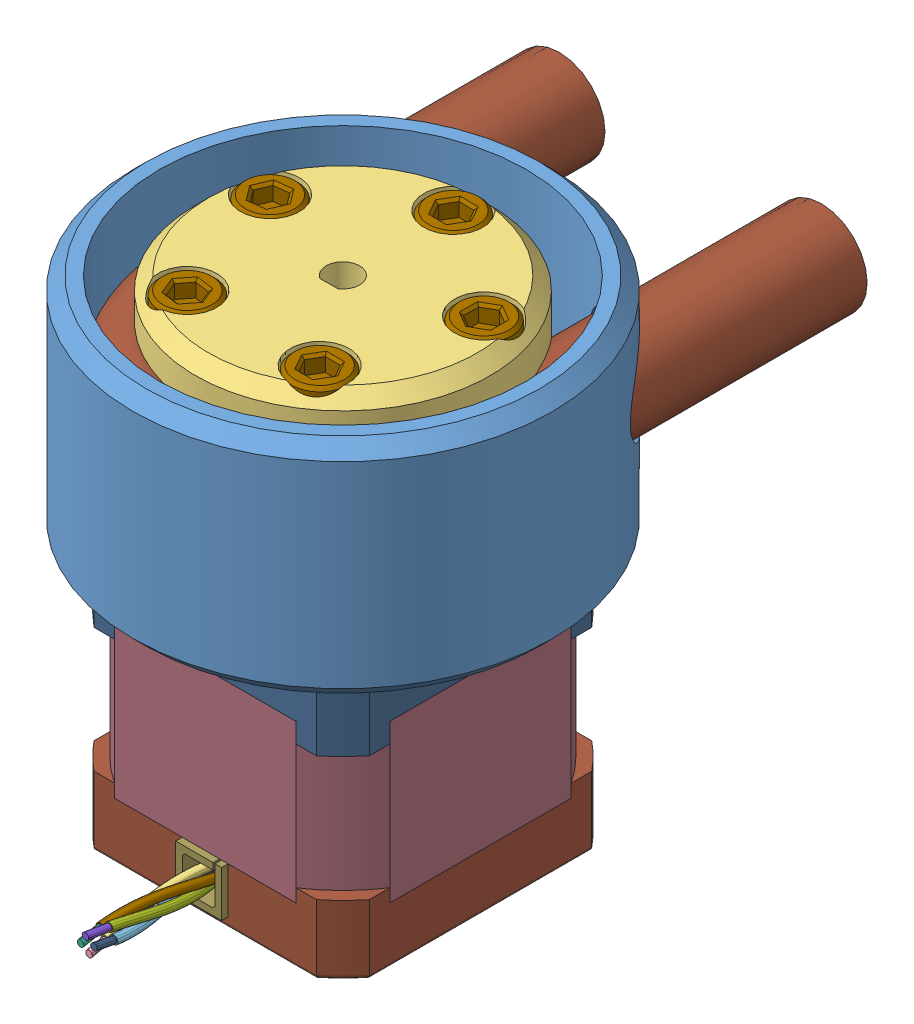
SolidWorks assembly pump, configuration Default. Lengths in mm.
Overall size (64 74.29 92).
174 component instances, 31 part files, 74 mates.
Components (placement in the parent):
- pump-shell-1: pump-shell [Default] at (23.8184 9.0777 41.5855) size (64 34 64)
- bottom-plate-1: bottom-plate [Default] at (23.8184 23.0777 41.5855) x (-0.999957 0 0.009262) z (0.009262 0 0.999957) size (52 18 52)
- top-plate-1: top-plate [Default] at (23.8184 35.0777 41.5855) x (-0.814427 0 -0.580267) z (0.580267 0 -0.814427) size (45 8.29 45)
- 625zz.STEP-1: 625zz.STEP [Default] at (23.8184 16.0777 41.5855) x (0 -1 0) z (-0.839089 0 -0.543994) size (5 16 16)
  - SKF 625 Inner Race^SKF 625.STEP-1: SKF 625 Inner Race^SKF 625.STEP [Default] at origin size (5 8.4 8.4)
  - SKF 625 Outer Race^SKF 625.STEP-1: SKF 625 Outer Race^SKF 625.STEP [Default] at origin size (5 16 16)
  - SKF 625 Ball^SKF 625.STEP-1: SKF 625 Ball^SKF 625.STEP [Default] at origin size (2.38 2.38 2.38)
  - SKF 625 Ball^SKF 625.STEP-2: SKF 625 Ball^SKF 625.STEP [Default] x (1 0 0) z (0 0.707107 0.707107) size (2.38 2.38 2.38)
  - SKF 625 Ball^SKF 625.STEP-3: SKF 625 Ball^SKF 625.STEP [Default] x (1 0 0) z (0 1 0) size (2.38 2.38 2.38)
  - SKF 625 Ball^SKF 625.STEP-4: SKF 625 Ball^SKF 625.STEP [Default] x (1 0 0) z (0 0.707107 -0.707107) size (2.38 2.38 2.38)
  - SKF 625 Ball^SKF 625.STEP-5: SKF 625 Ball^SKF 625.STEP [Default] x (1 0 0) z (0 0 -1) size (2.38 2.38 2.38)
  - SKF 625 Ball^SKF 625.STEP-6: SKF 625 Ball^SKF 625.STEP [Default] x (1 0 0) z (0 -0.707107 -0.707107) size (2.38 2.38 2.38)
  - SKF 625 Ball^SKF 625.STEP-7: SKF 625 Ball^SKF 625.STEP [Default] x (1 0 0) z (0 -1 0) size (2.38 2.38 2.38)
  - SKF 625 Ball^SKF 625.STEP-8: SKF 625 Ball^SKF 625.STEP [Default] x (1 0 0) z (0 -0.707107 0.707107) size (2.38 2.38 2.38)
  - SKF 625 Cage^SKF 625.STEP-1: SKF 625 Cage^SKF 625.STEP [Default] at (2.5 0 0) x (0 0 -1) z (1 0 0) size (12.17 12.17 2.88)
- m5-spacer-1: m5-spacer [Default] at (23.8184 16.0777 41.5855) x (-0.754389 0 0.656427) z (-0.656427 0 -0.754389) size (10 1 10)
- 625zz.STEP-2: 625zz.STEP [Default] at (7.5901 29.0777 36.4783) x (0 -1 0) z (0 0 1) size (5 16 16)
  - SKF 625 Inner Race^SKF 625.STEP-1: SKF 625 Inner Race^SKF 625.STEP [Default] at origin size (5 8.4 8.4)
  - SKF 625 Outer Race^SKF 625.STEP-1: SKF 625 Outer Race^SKF 625.STEP [Default] at origin size (5 16 16)
  - SKF 625 Ball^SKF 625.STEP-1: SKF 625 Ball^SKF 625.STEP [Default] at origin size (2.38 2.38 2.38)
  - SKF 625 Ball^SKF 625.STEP-2: SKF 625 Ball^SKF 625.STEP [Default] x (1 0 0) z (0 0.707107 0.707107) size (2.38 2.38 2.38)
  - SKF 625 Ball^SKF 625.STEP-3: SKF 625 Ball^SKF 625.STEP [Default] x (1 0 0) z (0 1 0) size (2.38 2.38 2.38)
  - SKF 625 Ball^SKF 625.STEP-4: SKF 625 Ball^SKF 625.STEP [Default] x (1 0 0) z (0 0.707107 -0.707107) size (2.38 2.38 2.38)
  - SKF 625 Ball^SKF 625.STEP-5: SKF 625 Ball^SKF 625.STEP [Default] x (1 0 0) z (0 0 -1) size (2.38 2.38 2.38)
  - SKF 625 Ball^SKF 625.STEP-6: SKF 625 Ball^SKF 625.STEP [Default] x (1 0 0) z (0 -0.707107 -0.707107) size (2.38 2.38 2.38)
  - SKF 625 Ball^SKF 625.STEP-7: SKF 625 Ball^SKF 625.STEP [Default] x (1 0 0) z (0 -1 0) size (2.38 2.38 2.38)
  - SKF 625 Ball^SKF 625.STEP-8: SKF 625 Ball^SKF 625.STEP [Default] x (1 0 0) z (0 -0.707107 0.707107) size (2.38 2.38 2.38)
  - SKF 625 Cage^SKF 625.STEP-1: SKF 625 Cage^SKF 625.STEP [Default] at (2.5 0 0) x (0 0 -1) z (1 0 0) size (12.17 12.17 2.88)
- 625zz.STEP-3: 625zz.STEP [Default] at (7.5901 34.0777 36.4783) x (0 -1 0) z (0.968021 0 0.25087) size (5 16 16)
  - SKF 625 Inner Race^SKF 625.STEP-1: SKF 625 Inner Race^SKF 625.STEP [Default] at origin size (5 8.4 8.4)
  - SKF 625 Outer Race^SKF 625.STEP-1: SKF 625 Outer Race^SKF 625.STEP [Default] at origin size (5 16 16)
  - SKF 625 Ball^SKF 625.STEP-1: SKF 625 Ball^SKF 625.STEP [Default] at origin size (2.38 2.38 2.38)
  - SKF 625 Ball^SKF 625.STEP-2: SKF 625 Ball^SKF 625.STEP [Default] x (1 0 0) z (0 0.707107 0.707107) size (2.38 2.38 2.38)
  - SKF 625 Ball^SKF 625.STEP-3: SKF 625 Ball^SKF 625.STEP [Default] x (1 0 0) z (0 1 0) size (2.38 2.38 2.38)
  - SKF 625 Ball^SKF 625.STEP-4: SKF 625 Ball^SKF 625.STEP [Default] x (1 0 0) z (0 0.707107 -0.707107) size (2.38 2.38 2.38)
  - SKF 625 Ball^SKF 625.STEP-5: SKF 625 Ball^SKF 625.STEP [Default] x (1 0 0) z (0 0 -1) size (2.38 2.38 2.38)
  - SKF 625 Ball^SKF 625.STEP-6: SKF 625 Ball^SKF 625.STEP [Default] x (1 0 0) z (0 -0.707107 -0.707107) size (2.38 2.38 2.38)
  - SKF 625 Ball^SKF 625.STEP-7: SKF 625 Ball^SKF 625.STEP [Default] x (1 0 0) z (0 -1 0) size (2.38 2.38 2.38)
  - SKF 625 Ball^SKF 625.STEP-8: SKF 625 Ball^SKF 625.STEP [Default] x (1 0 0) z (0 -0.707107 0.707107) size (2.38 2.38 2.38)
  - SKF 625 Cage^SKF 625.STEP-1: SKF 625 Cage^SKF 625.STEP [Default] at (2.5 0 0) x (0 0 -1) z (1 0 0) size (12.17 12.17 2.88)
- 625zz.STEP-4: 625zz.STEP [Default] at (33.9455 29.0777 55.2561) x (0 1 0) z (0 0 1) size (5 16 16)
  - SKF 625 Inner Race^SKF 625.STEP-1: SKF 625 Inner Race^SKF 625.STEP [Default] at origin size (5 8.4 8.4)
  - SKF 625 Outer Race^SKF 625.STEP-1: SKF 625 Outer Race^SKF 625.STEP [Default] at origin size (5 16 16)
  - SKF 625 Ball^SKF 625.STEP-1: SKF 625 Ball^SKF 625.STEP [Default] at origin size (2.38 2.38 2.38)
  - SKF 625 Ball^SKF 625.STEP-2: SKF 625 Ball^SKF 625.STEP [Default] x (1 0 0) z (0 0.707107 0.707107) size (2.38 2.38 2.38)
  - SKF 625 Ball^SKF 625.STEP-3: SKF 625 Ball^SKF 625.STEP [Default] x (1 0 0) z (0 1 0) size (2.38 2.38 2.38)
  - SKF 625 Ball^SKF 625.STEP-4: SKF 625 Ball^SKF 625.STEP [Default] x (1 0 0) z (0 0.707107 -0.707107) size (2.38 2.38 2.38)
  - SKF 625 Ball^SKF 625.STEP-5: SKF 625 Ball^SKF 625.STEP [Default] x (1 0 0) z (0 0 -1) size (2.38 2.38 2.38)
  - SKF 625 Ball^SKF 625.STEP-6: SKF 625 Ball^SKF 625.STEP [Default] x (1 0 0) z (0 -0.707107 -0.707107) size (2.38 2.38 2.38)
  - SKF 625 Ball^SKF 625.STEP-7: SKF 625 Ball^SKF 625.STEP [Default] x (1 0 0) z (0 -1 0) size (2.38 2.38 2.38)
  - SKF 625 Ball^SKF 625.STEP-8: SKF 625 Ball^SKF 625.STEP [Default] x (1 0 0) z (0 -0.707107 0.707107) size (2.38 2.38 2.38)
  - SKF 625 Cage^SKF 625.STEP-1: SKF 625 Cage^SKF 625.STEP [Default] at (2.5 0 0) x (0 0 -1) z (1 0 0) size (12.17 12.17 2.88)
- 625zz.STEP-5: 625zz.STEP [Default] at (33.9455 24.0777 55.2561) x (0 1 0) z (0.007155 0 0.999974) size (5 16 16)
  - SKF 625 Inner Race^SKF 625.STEP-1: SKF 625 Inner Race^SKF 625.STEP [Default] at origin size (5 8.4 8.4)
  - SKF 625 Outer Race^SKF 625.STEP-1: SKF 625 Outer Race^SKF 625.STEP [Default] at origin size (5 16 16)
  - SKF 625 Ball^SKF 625.STEP-1: SKF 625 Ball^SKF 625.STEP [Default] at origin size (2.38 2.38 2.38)
  - SKF 625 Ball^SKF 625.STEP-2: SKF 625 Ball^SKF 625.STEP [Default] x (1 0 0) z (0 0.707107 0.707107) size (2.38 2.38 2.38)
  - SKF 625 Ball^SKF 625.STEP-3: SKF 625 Ball^SKF 625.STEP [Default] x (1 0 0) z (0 1 0) size (2.38 2.38 2.38)
  - SKF 625 Ball^SKF 625.STEP-4: SKF 625 Ball^SKF 625.STEP [Default] x (1 0 0) z (0 0.707107 -0.707107) size (2.38 2.38 2.38)
  - SKF 625 Ball^SKF 625.STEP-5: SKF 625 Ball^SKF 625.STEP [Default] x (1 0 0) z (0 0 -1) size (2.38 2.38 2.38)
  - SKF 625 Ball^SKF 625.STEP-6: SKF 625 Ball^SKF 625.STEP [Default] x (1 0 0) z (0 -0.707107 -0.707107) size (2.38 2.38 2.38)
  - SKF 625 Ball^SKF 625.STEP-7: SKF 625 Ball^SKF 625.STEP [Default] x (1 0 0) z (0 -1 0) size (2.38 2.38 2.38)
  - SKF 625 Ball^SKF 625.STEP-8: SKF 625 Ball^SKF 625.STEP [Default] x (1 0 0) z (0 -0.707107 0.707107) size (2.38 2.38 2.38)
  - SKF 625 Cage^SKF 625.STEP-1: SKF 625 Cage^SKF 625.STEP [Default] at (2.5 0 0) x (0 0 -1) z (1 0 0) size (12.17 12.17 2.88)
- 625zz.STEP-6: 625zz.STEP [Default] at (13.9463 29.0777 55.4414) x (0 1 0) z (0.26967 0 0.962953) size (5 16 16)
  - SKF 625 Inner Race^SKF 625.STEP-1: SKF 625 Inner Race^SKF 625.STEP [Default] at origin size (5 8.4 8.4)
  - SKF 625 Outer Race^SKF 625.STEP-1: SKF 625 Outer Race^SKF 625.STEP [Default] at origin size (5 16 16)
  - SKF 625 Ball^SKF 625.STEP-1: SKF 625 Ball^SKF 625.STEP [Default] at origin size (2.38 2.38 2.38)
  - SKF 625 Ball^SKF 625.STEP-2: SKF 625 Ball^SKF 625.STEP [Default] x (1 0 0) z (0 0.707107 0.707107) size (2.38 2.38 2.38)
  - SKF 625 Ball^SKF 625.STEP-3: SKF 625 Ball^SKF 625.STEP [Default] x (1 0 0) z (0 1 0) size (2.38 2.38 2.38)
  - SKF 625 Ball^SKF 625.STEP-4: SKF 625 Ball^SKF 625.STEP [Default] x (1 0 0) z (0 0.707107 -0.707107) size (2.38 2.38 2.38)
  - SKF 625 Ball^SKF 625.STEP-5: SKF 625 Ball^SKF 625.STEP [Default] x (1 0 0) z (0 0 -1) size (2.38 2.38 2.38)
  - SKF 625 Ball^SKF 625.STEP-6: SKF 625 Ball^SKF 625.STEP [Default] x (1 0 0) z (0 -0.707107 -0.707107) size (2.38 2.38 2.38)
  - SKF 625 Ball^SKF 625.STEP-7: SKF 625 Ball^SKF 625.STEP [Default] x (1 0 0) z (0 -1 0) size (2.38 2.38 2.38)
  - SKF 625 Ball^SKF 625.STEP-8: SKF 625 Ball^SKF 625.STEP [Default] x (1 0 0) z (0 -0.707107 0.707107) size (2.38 2.38 2.38)
  - SKF 625 Cage^SKF 625.STEP-1: SKF 625 Cage^SKF 625.STEP [Default] at (2.5 0 0) x (0 0 -1) z (1 0 0) size (12.17 12.17 2.88)
- 625zz.STEP-7: 625zz.STEP [Default] at (13.9463 24.0777 55.4414) x (0 1 0) z (0.019727 0 0.999805) size (5 16 16)
  - SKF 625 Inner Race^SKF 625.STEP-1: SKF 625 Inner Race^SKF 625.STEP [Default] at origin size (5 8.4 8.4)
  - SKF 625 Outer Race^SKF 625.STEP-1: SKF 625 Outer Race^SKF 625.STEP [Default] at origin size (5 16 16)
  - SKF 625 Ball^SKF 625.STEP-1: SKF 625 Ball^SKF 625.STEP [Default] at origin size (2.38 2.38 2.38)
  - SKF 625 Ball^SKF 625.STEP-2: SKF 625 Ball^SKF 625.STEP [Default] x (1 0 0) z (0 0.707107 0.707107) size (2.38 2.38 2.38)
  - SKF 625 Ball^SKF 625.STEP-3: SKF 625 Ball^SKF 625.STEP [Default] x (1 0 0) z (0 1 0) size (2.38 2.38 2.38)
  - SKF 625 Ball^SKF 625.STEP-4: SKF 625 Ball^SKF 625.STEP [Default] x (1 0 0) z (0 0.707107 -0.707107) size (2.38 2.38 2.38)
  - SKF 625 Ball^SKF 625.STEP-5: SKF 625 Ball^SKF 625.STEP [Default] x (1 0 0) z (0 0 -1) size (2.38 2.38 2.38)
  - SKF 625 Ball^SKF 625.STEP-6: SKF 625 Ball^SKF 625.STEP [Default] x (1 0 0) z (0 -0.707107 -0.707107) size (2.38 2.38 2.38)
  - SKF 625 Ball^SKF 625.STEP-7: SKF 625 Ball^SKF 625.STEP [Default] x (1 0 0) z (0 -1 0) size (2.38 2.38 2.38)
  - SKF 625 Ball^SKF 625.STEP-8: SKF 625 Ball^SKF 625.STEP [Default] x (1 0 0) z (0 -0.707107 0.707107) size (2.38 2.38 2.38)
  - SKF 625 Cage^SKF 625.STEP-1: SKF 625 Cage^SKF 625.STEP [Default] at (2.5 0 0) x (0 0 -1) z (1 0 0) size (12.17 12.17 2.88)
- m5-spacer-2: m5-spacer [Default] at (13.9463 34.0777 55.4414) size (10 1 10)
- m5-spacer-3: m5-spacer [Default] at (13.9463 24.0777 55.4414) x (-0.837169 0 -0.546944) z (-0.546944 0 0.837169) size (10 1 10)
- m5-spacer-4: m5-spacer [Default] at (33.9455 24.0777 55.2561) x (-0.837169 0 -0.546944) z (-0.546944 0 0.837169) size (10 1 10)
- m5-spacer-5: m5-spacer [Default] at (39.9494 24.0777 36.1786) x (-0.837169 0 -0.546944) z (-0.546944 0 0.837169) size (10 1 10)
- m5-spacer-6: m5-spacer [Default] at (33.9455 34.0777 55.2561) size (10 1 10)
- m5-spacer-7: m5-spacer [Default] at (7.5901 34.0777 36.4783) x (-1 0 0) z (0 0 -1) size (10 1 10)
- m5-spacer-8: m5-spacer [Default] at (39.9494 34.0777 36.1786) x (-1 0 0) z (0 0 -1) size (10 1 10)
- m5-spacer-9: m5-spacer [Default] at (23.6609 34.0777 24.5732) x (-1 0 0) z (0 0 -1) size (10 1 10)
- m5-spacer-10: m5-spacer [Default] at (23.6609 24.0777 24.5732) x (-0.837169 0 -0.546944) z (-0.546944 0 0.837169) size (10 1 10)
- m5-spacer-11: m5-spacer [Default] at (7.5901 24.0777 36.4783) x (-0.837169 0 -0.546944) z (-0.546944 0 0.837169) size (10 1 10)
- 625zz.STEP-8: 625zz.STEP [Default] at (39.9494 34.0777 36.1786) x (0 -1 0) z (0.880718 0 0.47364) size (5 16 16)
  - SKF 625 Inner Race^SKF 625.STEP-1: SKF 625 Inner Race^SKF 625.STEP [Default] at origin size (5 8.4 8.4)
  - SKF 625 Outer Race^SKF 625.STEP-1: SKF 625 Outer Race^SKF 625.STEP [Default] at origin size (5 16 16)
  - SKF 625 Ball^SKF 625.STEP-1: SKF 625 Ball^SKF 625.STEP [Default] at origin size (2.38 2.38 2.38)
  - SKF 625 Ball^SKF 625.STEP-2: SKF 625 Ball^SKF 625.STEP [Default] x (1 0 0) z (0 0.707107 0.707107) size (2.38 2.38 2.38)
  - SKF 625 Ball^SKF 625.STEP-3: SKF 625 Ball^SKF 625.STEP [Default] x (1 0 0) z (0 1 0) size (2.38 2.38 2.38)
  - SKF 625 Ball^SKF 625.STEP-4: SKF 625 Ball^SKF 625.STEP [Default] x (1 0 0) z (0 0.707107 -0.707107) size (2.38 2.38 2.38)
  - SKF 625 Ball^SKF 625.STEP-5: SKF 625 Ball^SKF 625.STEP [Default] x (1 0 0) z (0 0 -1) size (2.38 2.38 2.38)
  - SKF 625 Ball^SKF 625.STEP-6: SKF 625 Ball^SKF 625.STEP [Default] x (1 0 0) z (0 -0.707107 -0.707107) size (2.38 2.38 2.38)
  - SKF 625 Ball^SKF 625.STEP-7: SKF 625 Ball^SKF 625.STEP [Default] x (1 0 0) z (0 -1 0) size (2.38 2.38 2.38)
  - SKF 625 Ball^SKF 625.STEP-8: SKF 625 Ball^SKF 625.STEP [Default] x (1 0 0) z (0 -0.707107 0.707107) size (2.38 2.38 2.38)
  - SKF 625 Cage^SKF 625.STEP-1: SKF 625 Cage^SKF 625.STEP [Default] at (2.5 0 0) x (0 0 -1) z (1 0 0) size (12.17 12.17 2.88)
- 625zz.STEP-9: 625zz.STEP [Default] at (39.9494 29.0777 36.1786) x (0 -1 0) z (0.968021 0 0.25087) size (5 16 16)
  - SKF 625 Inner Race^SKF 625.STEP-1: SKF 625 Inner Race^SKF 625.STEP [Default] at origin size (5 8.4 8.4)
  - SKF 625 Outer Race^SKF 625.STEP-1: SKF 625 Outer Race^SKF 625.STEP [Default] at origin size (5 16 16)
  - SKF 625 Ball^SKF 625.STEP-1: SKF 625 Ball^SKF 625.STEP [Default] at origin size (2.38 2.38 2.38)
  - SKF 625 Ball^SKF 625.STEP-2: SKF 625 Ball^SKF 625.STEP [Default] x (1 0 0) z (0 0.707107 0.707107) size (2.38 2.38 2.38)
  - SKF 625 Ball^SKF 625.STEP-3: SKF 625 Ball^SKF 625.STEP [Default] x (1 0 0) z (0 1 0) size (2.38 2.38 2.38)
  - SKF 625 Ball^SKF 625.STEP-4: SKF 625 Ball^SKF 625.STEP [Default] x (1 0 0) z (0 0.707107 -0.707107) size (2.38 2.38 2.38)
  - SKF 625 Ball^SKF 625.STEP-5: SKF 625 Ball^SKF 625.STEP [Default] x (1 0 0) z (0 0 -1) size (2.38 2.38 2.38)
  - SKF 625 Ball^SKF 625.STEP-6: SKF 625 Ball^SKF 625.STEP [Default] x (1 0 0) z (0 -0.707107 -0.707107) size (2.38 2.38 2.38)
  - SKF 625 Ball^SKF 625.STEP-7: SKF 625 Ball^SKF 625.STEP [Default] x (1 0 0) z (0 -1 0) size (2.38 2.38 2.38)
  - SKF 625 Ball^SKF 625.STEP-8: SKF 625 Ball^SKF 625.STEP [Default] x (1 0 0) z (0 -0.707107 0.707107) size (2.38 2.38 2.38)
  - SKF 625 Cage^SKF 625.STEP-1: SKF 625 Cage^SKF 625.STEP [Default] at (2.5 0 0) x (0 0 -1) z (1 0 0) size (12.17 12.17 2.88)
- 625zz.STEP-10: 625zz.STEP [Default] at (23.6609 34.0777 24.5732) x (0 -1 0) z (0.667894 0 -0.744257) size (5 16 16)
  - SKF 625 Inner Race^SKF 625.STEP-1: SKF 625 Inner Race^SKF 625.STEP [Default] at origin size (5 8.4 8.4)
  - SKF 625 Outer Race^SKF 625.STEP-1: SKF 625 Outer Race^SKF 625.STEP [Default] at origin size (5 16 16)
  - SKF 625 Ball^SKF 625.STEP-1: SKF 625 Ball^SKF 625.STEP [Default] at origin size (2.38 2.38 2.38)
  - SKF 625 Ball^SKF 625.STEP-2: SKF 625 Ball^SKF 625.STEP [Default] x (1 0 0) z (0 0.707107 0.707107) size (2.38 2.38 2.38)
  - SKF 625 Ball^SKF 625.STEP-3: SKF 625 Ball^SKF 625.STEP [Default] x (1 0 0) z (0 1 0) size (2.38 2.38 2.38)
  - SKF 625 Ball^SKF 625.STEP-4: SKF 625 Ball^SKF 625.STEP [Default] x (1 0 0) z (0 0.707107 -0.707107) size (2.38 2.38 2.38)
  - SKF 625 Ball^SKF 625.STEP-5: SKF 625 Ball^SKF 625.STEP [Default] x (1 0 0) z (0 0 -1) size (2.38 2.38 2.38)
  - SKF 625 Ball^SKF 625.STEP-6: SKF 625 Ball^SKF 625.STEP [Default] x (1 0 0) z (0 -0.707107 -0.707107) size (2.38 2.38 2.38)
  - SKF 625 Ball^SKF 625.STEP-7: SKF 625 Ball^SKF 625.STEP [Default] x (1 0 0) z (0 -1 0) size (2.38 2.38 2.38)
  - SKF 625 Ball^SKF 625.STEP-8: SKF 625 Ball^SKF 625.STEP [Default] x (1 0 0) z (0 -0.707107 0.707107) size (2.38 2.38 2.38)
  - SKF 625 Cage^SKF 625.STEP-1: SKF 625 Cage^SKF 625.STEP [Default] at (2.5 0 0) x (0 0 -1) z (1 0 0) size (12.17 12.17 2.88)
- 625zz.STEP-11: 625zz.STEP [Default] at (23.6609 29.0777 24.5732) x (0 -1 0) z (0.968021 0 0.25087) size (5 16 16)
  - SKF 625 Inner Race^SKF 625.STEP-1: SKF 625 Inner Race^SKF 625.STEP [Default] at origin size (5 8.4 8.4)
  - SKF 625 Outer Race^SKF 625.STEP-1: SKF 625 Outer Race^SKF 625.STEP [Default] at origin size (5 16 16)
  - SKF 625 Ball^SKF 625.STEP-1: SKF 625 Ball^SKF 625.STEP [Default] at origin size (2.38 2.38 2.38)
  - SKF 625 Ball^SKF 625.STEP-2: SKF 625 Ball^SKF 625.STEP [Default] x (1 0 0) z (0 0.707107 0.707107) size (2.38 2.38 2.38)
  - SKF 625 Ball^SKF 625.STEP-3: SKF 625 Ball^SKF 625.STEP [Default] x (1 0 0) z (0 1 0) size (2.38 2.38 2.38)
  - SKF 625 Ball^SKF 625.STEP-4: SKF 625 Ball^SKF 625.STEP [Default] x (1 0 0) z (0 0.707107 -0.707107) size (2.38 2.38 2.38)
  - SKF 625 Ball^SKF 625.STEP-5: SKF 625 Ball^SKF 625.STEP [Default] x (1 0 0) z (0 0 -1) size (2.38 2.38 2.38)
  - SKF 625 Ball^SKF 625.STEP-6: SKF 625 Ball^SKF 625.STEP [Default] x (1 0 0) z (0 -0.707107 -0.707107) size (2.38 2.38 2.38)
  - SKF 625 Ball^SKF 625.STEP-7: SKF 625 Ball^SKF 625.STEP [Default] x (1 0 0) z (0 -1 0) size (2.38 2.38 2.38)
  - SKF 625 Ball^SKF 625.STEP-8: SKF 625 Ball^SKF 625.STEP [Default] x (1 0 0) z (0 -0.707107 0.707107) size (2.38 2.38 2.38)
  - SKF 625 Cage^SKF 625.STEP-1: SKF 625 Cage^SKF 625.STEP [Default] at (2.5 0 0) x (0 0 -1) z (1 0 0) size (12.17 12.17 2.88)
- m5-socket-23-1: m5-socket-23 [Default] at (23.6609 43.0777 24.5732) x (0 -1 0) z (-0.50599 0 0.862539) size (28 8.5 8.5)
- m5-socket-23-2: m5-socket-23 [Default] at (39.9494 43.0777 36.1786) x (0 -1 0) z (-0.86182 0 -0.507214) size (28 8.5 8.5)
- m5-socket-23-3: m5-socket-23 [Default] at (33.9455 43.0777 55.2561) x (0 -1 0) z (-0.50599 0 0.862539) size (28 8.5 8.5)
- m5-socket-23-4: m5-socket-23 [Default] at (13.9463 43.0777 55.4414) x (0 -1 0) z (-0.617121 0 0.786868) size (28 8.5 8.5)
- m5-socket-23-5: m5-socket-23 [Default] at (7.5901 43.0777 36.4783) x (0 -1 0) z (0.992432 0 -0.122792) size (28 8.5 8.5)
- nema17-40mm.step-1: nema17-40mm.step [Default] at (23.8184 9.0777 41.5855) x (-1 0 0) z (0 0 1) size (42 64 60)
  - Frontplate.step-1: Frontplate.step [Default] at (0 10.5 0) size (42 12.5 42)
  - Backplate.step-1: Backplate.step [Default] at (0 40 0) size (42 10.5 42)
  - Connenctor.step-1: Connenctor.step [Default] at (0 31.5 22) size (7 7 7)
  - Housing.step-1: Housing.step [Default] at (0 7.5 0) size (42 24 42)
  - Bearing dummy.step-1: Bearing dummy.step [Default] at (0 4 0) size (22 7 22)
  - Bearing dummy 01.step-1: Bearing dummy 01.step [Default] at (0 35 0) size (22 7 22)
  - Core.step-1: Core.step [Default] at origin size (30 62.5 30)
  - M3x34-Screw.step-1: M3x34-Screw.step [Default] at (15.5 37.6 15.5) x (1 0 0) z (0 1 0) size (5.5 5.5 36)
  - M3x34-Screw001.step-1: M3x34-Screw001.step [Default] at (-15.5 37.6 15.5) x (1 0 0) z (0 1 0) size (5.5 5.5 36)
  - M3x34-Screw002.step-1: M3x34-Screw002.step [Default] at (-15.5 37.6 -15.5) x (1 0 0) z (0 1 0) size (5.5 5.5 36)
  - M3x34-Screw003.step-1: M3x34-Screw003.step [Default] at (15.5 37.6 -15.5) x (1 0 0) z (0 1 0) size (5.5 5.5 36)
  - Cable-1of4.step-1: Cable-1of4.step [Default] at (0 35 0) size (3.44 3.69 21)
  - Copper-1of4.step-1: Copper-1of4.step [Default] at (0 35 0) size (2.77 3.05 24)
  - Cable-2of4.step-1: Cable-2of4.step [Default] at (0 35 0) x (0 1 0) z (0 0 1) size (3.44 3.69 21)
  - Copper-4of4.step-1: Copper-4of4.step [Default] at (0 35 0) x (0 -1 0) z (0 0 1) size (2.77 3.05 24)
  - Cable-3of4.step-1: Cable-3of4.step [Default] at (0 35 0) x (-1 0 0) z (0 0 1) size (3.44 3.69 21)
  - Copper-3of4.step-1: Copper-3of4.step [Default] at (0 35 0) x (-1 0 0) z (0 0 1) size (2.77 3.05 24)
  - Cable-4of4.step-1: Cable-4of4.step [Default] at (0 35 0) x (0 -1 0) z (0 0 1) size (3.44 3.69 21)
  - Copper-2of4.step-1: Copper-2of4.step [Default] at (0 35 0) x (0 1 0) z (0 0 1) size (2.77 3.05 24)
- silicone-tube-1: silicone-tube [Default] at (23.8184 29.0777 43.5855) x (0 0 -1) z (0 1 0) size (83.5 54.86 16.16)
- m3-nut-1: m3-nut [Default] at (23.8661 29.0777 46.7353) x (0.955477 0.294934 -0.00885) z (0.009262 0 0.999957) size (5.8 5.57 2.34)
- m3-round-6-1: m3-round-6 [m3-10] at (23.8818 29.0777 48.4307) x (0.974551 -0.223985 -0.009027) z (-0.223976 -0.974593 0.002075) size (5.7 7.65 5.7)
Mates (geometry in assembly coordinates):
- Concentric1: concentric anti-aligned: cylinder of pump-shell-1 through (23.8184 9.0777 41.5855) axis (0 1 0) radius 12.5; cylinder of 625zz.STEP-1/SKF 625 Outer Race^SKF 625.STEP-1 through (23.8184 11.3777 41.5855) axis (0 -1 0) radius 8
- Concentric2: concentric aligned: cylinder of 625zz.STEP-1/SKF 625 Inner Race^SKF 625.STEP-1 through (23.8184 11.3777 41.5855) axis (0 -1 0) radius 2.5; cylinder of m5-spacer-1 through (23.8184 17.0777 41.5855) axis (0 -1 0) radius 2.6
- Coincident2: coincident anti-aligned: plane of 625zz.STEP-1/SKF 625 Inner Race^SKF 625.STEP-1 through (21.5881 16.0777 45.0258) normal (0 1 0); plane of m5-spacer-1 through (23.8184 16.0777 41.5855) normal (0 -1 0)
- Coincident3: coincident anti-aligned: plane of bottom-plate-1 through (23.8184 17.0777 41.5855) normal (0 -1 0); plane of m5-spacer-1 through (23.8184 17.0777 41.5855) normal (0 1 0)
- Concentric3: concentric anti-aligned: cylinder of pump-shell-1 through (23.8184 43.0777 41.5855) axis (0 -1 0) radius 28; cylinder of bottom-plate-1 through (23.8184 17.0777 41.5855) axis (0 1 0) radius 26
- Coincident4: coincident anti-aligned: plane of bottom-plate-1 through (18.8824 35.0777 48.5134) normal (0 1 0); plane of top-plate-1 through (23.8184 35.0777 41.5855) normal (0 -1 0)
- Concentric5: concentric aligned: cylinder of bottom-plate-1 through (13.9463 17.0777 55.4414) axis (0 1 0) radius 2.65; cylinder of 625zz.STEP-7/SKF 625 Inner Race^SKF 625.STEP-1 through (13.9463 28.7777 55.4414) axis (0 1 0) radius 2.5
- Coincident7: coincident anti-aligned: plane of 625zz.STEP-6/SKF 625 Outer Race^SKF 625.STEP-1 through (6.5316 29.0777 57.5178) normal (0 -1 0); plane of 625zz.STEP-7/SKF 625 Outer Race^SKF 625.STEP-1 through (7.2976 29.0777 55.5725) normal (0 1 0)
- Concentric6: concentric aligned: cylinder of 625zz.STEP-6/SKF 625 Outer Race^SKF 625.STEP-1 through (13.9463 33.7777 55.4414) axis (0 1 0) radius 8; cylinder of 625zz.STEP-7/SKF 625 Outer Race^SKF 625.STEP-1 through (13.9463 28.7777 55.4414) axis (0 1 0) radius 8
- Coincident8: coincident anti-aligned: plane of top-plate-1 through (23.8184 35.0777 41.5855) normal (0 -1 0); plane of m5-spacer-2 through (13.9463 35.0777 55.4414) normal (0 1 0)
- Concentric7: concentric anti-aligned: cylinder of 625zz.STEP-6/SKF 625 Outer Race^SKF 625.STEP-1 through (13.9463 33.7777 55.4414) axis (0 1 0) radius 8; cylinder of m5-spacer-2 through (13.9463 35.0777 55.4414) axis (0 -1 0) radius 5
- Coincident9: coincident anti-aligned: plane of bottom-plate-1 through (23.8184 23.0777 41.5855) normal (0 1 0); plane of m5-spacer-3 through (13.9463 23.0777 55.4414) normal (0 -1 0)
- Concentric8: concentric aligned: cylinder of 625zz.STEP-7/SKF 625 Outer Race^SKF 625.STEP-1 through (13.9463 28.7777 55.4414) axis (0 1 0) radius 8; cylinder of m5-spacer-3 through (13.9463 23.0777 55.4414) axis (0 1 0) radius 5
- Coincident10: coincident anti-aligned: plane of bottom-plate-1 through (23.8184 23.0777 41.5855) normal (0 1 0); plane of m5-spacer-4 through (33.9455 23.0777 55.2561) normal (0 -1 0)
- Concentric9: concentric aligned: cylinder of bottom-plate-1 through (33.9455 17.0777 55.2561) axis (0 1 0) radius 2.65; cylinder of m5-spacer-4 through (33.9455 23.0777 55.2561) axis (0 1 0) radius 2.6
- Coincident11: coincident anti-aligned: plane of 625zz.STEP-5/SKF 625 Outer Race^SKF 625.STEP-1 through (26.2457 24.0777 55.3112) normal (0 -1 0); plane of m5-spacer-4 through (33.9455 24.0777 55.2561) normal (0 1 0)
- Concentric10: concentric aligned: cylinder of bottom-plate-1 through (33.9455 17.0777 55.2561) axis (0 1 0) radius 2.65; cylinder of 625zz.STEP-5/SKF 625 Outer Race^SKF 625.STEP-1 through (33.9455 28.7777 55.2561) axis (0 1 0) radius 8
- Coincident12: coincident anti-aligned: plane of 625zz.STEP-4/SKF 625 Outer Race^SKF 625.STEP-1 through (26.2455 29.0777 55.2561) normal (0 -1 0); plane of 625zz.STEP-5/SKF 625 Outer Race^SKF 625.STEP-1 through (27.2957 29.0777 55.3037) normal (0 1 0)
- Concentric11: concentric aligned: cylinder of 625zz.STEP-4/SKF 625 Outer Race^SKF 625.STEP-1 through (33.9455 33.7777 55.2561) axis (0 1 0) radius 8; cylinder of 625zz.STEP-5/SKF 625 Outer Race^SKF 625.STEP-1 through (33.9455 28.7777 55.2561) axis (0 1 0) radius 8
- Coincident13: coincident anti-aligned: plane of top-plate-1 through (23.8184 35.0777 41.5855) normal (0 -1 0); plane of m5-spacer-6 through (33.9455 35.0777 55.2561) normal (0 1 0)
- Concentric12: concentric anti-aligned: cylinder of 625zz.STEP-4/SKF 625 Inner Race^SKF 625.STEP-1 through (33.9455 33.7777 55.2561) axis (0 1 0) radius 2.5; cylinder of m5-spacer-6 through (33.9455 35.0777 55.2561) axis (0 -1 0) radius 2.6
- Coincident14: coincident anti-aligned: plane of bottom-plate-1 through (23.8184 23.0777 41.5855) normal (0 1 0); plane of m5-spacer-5 through (39.9494 23.0777 36.1786) normal (0 -1 0)
- Concentric14: concentric aligned: cylinder of bottom-plate-1 through (39.9494 17.0777 36.1786) axis (0 1 0) radius 2.65; cylinder of m5-spacer-5 through (39.9494 23.0777 36.1786) axis (0 1 0) radius 2.6
- Concentric15: concentric aligned: cylinder of bottom-plate-1 through (23.6609 17.0777 24.5732) axis (0 1 0) radius 2.65; cylinder of m5-spacer-10 through (23.6609 23.0777 24.5732) axis (0 1 0) radius 2.6
- Coincident15: coincident anti-aligned: plane of bottom-plate-1 through (23.8184 23.0777 41.5855) normal (0 1 0); plane of m5-spacer-10 through (23.6609 23.0777 24.5732) normal (0 -1 0)
- Coincident16: coincident anti-aligned: plane of bottom-plate-1 through (23.8184 23.0777 41.5855) normal (0 1 0); plane of m5-spacer-11 through (7.5901 23.0777 36.4783) normal (0 -1 0)
- Concentric16: concentric aligned: cylinder of bottom-plate-1 through (7.5901 17.0777 36.4783) axis (0 1 0) radius 2.65; cylinder of m5-spacer-11 through (7.5901 23.0777 36.4783) axis (0 1 0) radius 2.6
- Coincident17: coincident anti-aligned: plane of 625zz.STEP-2/SKF 625 Inner Race^SKF 625.STEP-1 through (10.3901 24.0777 36.4783) normal (0 -1 0); plane of m5-spacer-11 through (7.5901 24.0777 36.4783) normal (0 1 0)
- Concentric17: concentric anti-aligned: cylinder of bottom-plate-1 through (7.5901 17.0777 36.4783) axis (0 1 0) radius 2.65; cylinder of 625zz.STEP-2/SKF 625 Outer Race^SKF 625.STEP-1 through (7.5901 24.3777 36.4783) axis (0 -1 0) radius 8
- Coincident18: coincident anti-aligned: plane of 625zz.STEP-2/SKF 625 Outer Race^SKF 625.STEP-1 through (15.2901 29.0777 36.4783) normal (0 1 0); plane of 625zz.STEP-3/SKF 625 Outer Race^SKF 625.STEP-1 through (9.2584 29.0777 30.041) normal (0 -1 0)
- Concentric18: concentric aligned: cylinder of 625zz.STEP-2/SKF 625 Outer Race^SKF 625.STEP-1 through (7.5901 24.3777 36.4783) axis (0 -1 0) radius 8; cylinder of 625zz.STEP-3/SKF 625 Outer Race^SKF 625.STEP-1 through (7.5901 29.3777 36.4783) axis (0 -1 0) radius 8
- Coincident19: coincident anti-aligned: plane of 625zz.STEP-3/SKF 625 Outer Race^SKF 625.STEP-1 through (9.5218 34.0777 29.0245) normal (0 1 0); plane of m5-spacer-7 through (7.5901 34.0777 36.4783) normal (0 -1 0)
- Concentric19: concentric aligned: cylinder of 625zz.STEP-3/SKF 625 Inner Race^SKF 625.STEP-1 through (7.5901 29.3777 36.4783) axis (0 -1 0) radius 2.5; cylinder of m5-spacer-7 through (7.5901 35.0777 36.4783) axis (0 -1 0) radius 5
- Coincident20: coincident anti-aligned: plane of m5-spacer-5 through (39.9494 24.0777 36.1786) normal (0 1 0); plane of 625zz.STEP-9/SKF 625 Inner Race^SKF 625.STEP-1 through (40.6518 24.0777 33.4681) normal (0 -1 0)
- Concentric20: concentric anti-aligned: cylinder of bottom-plate-1 through (39.9494 17.0777 36.1786) axis (0 1 0) radius 2.65; cylinder of 625zz.STEP-9/SKF 625 Outer Race^SKF 625.STEP-1 through (39.9494 24.3777 36.1786) axis (0 -1 0) radius 8
- Concentric21: concentric aligned: cylinder of 625zz.STEP-8/SKF 625 Outer Race^SKF 625.STEP-1 through (39.9494 29.3777 36.1786) axis (0 -1 0) radius 8; cylinder of 625zz.STEP-9/SKF 625 Outer Race^SKF 625.STEP-1 through (39.9494 24.3777 36.1786) axis (0 -1 0) radius 8
- Coincident21: coincident anti-aligned: plane of 625zz.STEP-8/SKF 625 Outer Race^SKF 625.STEP-1 through (43.0991 29.0777 30.3218) normal (0 -1 0); plane of 625zz.STEP-9/SKF 625 Outer Race^SKF 625.STEP-1 through (41.8811 29.0777 28.7248) normal (0 1 0)
- Coincident22: coincident anti-aligned: plane of m5-spacer-8 through (39.9494 34.0777 36.1786) normal (0 -1 0); plane of 625zz.STEP-8/SKF 625 Inner Race^SKF 625.STEP-1 through (41.8913 34.0777 32.5676) normal (0 1 0)
- Concentric22: concentric aligned: cylinder of m5-spacer-8 through (39.9494 35.0777 36.1786) axis (0 -1 0) radius 5; cylinder of 625zz.STEP-8/SKF 625 Inner Race^SKF 625.STEP-1 through (39.9494 29.3777 36.1786) axis (0 -1 0) radius 2.5
- Coincident23: coincident anti-aligned: plane of top-plate-1 through (23.8184 35.0777 41.5855) normal (0 -1 0); plane of m5-spacer-9 through (23.6609 35.0777 24.5732) normal (0 1 0)
- Concentric23: concentric anti-aligned: cylinder of m5-spacer-9 through (23.6609 35.0777 24.5732) axis (0 -1 0) radius 2.6; cylinder of m5-spacer-10 through (23.6609 23.0777 24.5732) axis (0 1 0) radius 2.6
- Concentric24: concentric anti-aligned: cylinder of bottom-plate-1 through (23.6609 17.0777 24.5732) axis (0 1 0) radius 2.65; cylinder of 625zz.STEP-11/SKF 625 Outer Race^SKF 625.STEP-1 through (23.6609 24.3777 24.5732) axis (0 -1 0) radius 8
- Coincident24: coincident anti-aligned: plane of m5-spacer-10 through (23.6609 24.0777 24.5732) normal (0 1 0); plane of 625zz.STEP-11/SKF 625 Outer Race^SKF 625.STEP-1 through (25.3291 24.0777 18.1359) normal (0 -1 0)
- Concentric25: concentric aligned: cylinder of 625zz.STEP-10/SKF 625 Outer Race^SKF 625.STEP-1 through (23.6609 29.3777 24.5732) axis (0 -1 0) radius 8; cylinder of 625zz.STEP-11/SKF 625 Outer Race^SKF 625.STEP-1 through (23.6609 24.3777 24.5732) axis (0 -1 0) radius 8
- Coincident25: coincident anti-aligned: plane of 625zz.STEP-10/SKF 625 Outer Race^SKF 625.STEP-1 through (18.7115 29.0777 20.1317) normal (0 -1 0); plane of 625zz.STEP-11/SKF 625 Outer Race^SKF 625.STEP-1 through (25.5926 29.0777 17.1195) normal (0 1 0)
- Concentric30: concentric anti-aligned: cylinder of bottom-plate-1 through (23.8184 17.0777 41.5855) axis (0 1 0) radius 26; cylinder of top-plate-1 through (23.8184 43.0777 41.5855) axis (0 -1 0) radius 22.5
- Coincident31: coincident anti-aligned: plane of top-plate-1 through (23.6609 38.0777 24.5732) normal (0 1 0); plane of m5-socket-23-1 through (25.8069 38.0777 25.8321) normal (0 -1 0)
- Concentric36: concentric anti-aligned: cylinder of top-plate-1 through (23.6609 43.0777 24.5732) axis (0 -1 0) radius 2.65; cylinder of m5-socket-23-1 through (23.6609 131.7832 24.5732) axis (0 1 0) radius 2.488
- Concentric37: concentric anti-aligned: cylinder of top-plate-1 through (39.9494 43.0777 36.1786) axis (0 -1 0) radius 2.65; cylinder of m5-socket-23-2 through (39.9494 131.7832 36.1786) axis (0 1 0) radius 2.488
- Coincident32: coincident anti-aligned: plane of top-plate-1 through (39.9494 38.0777 36.1786) normal (0 1 0); plane of m5-socket-23-2 through (38.6874 38.0777 38.3228) normal (0 -1 0)
- Concentric38: concentric anti-aligned: cylinder of top-plate-1 through (33.9455 43.0777 55.2561) axis (0 -1 0) radius 2.65; cylinder of m5-socket-23-3 through (33.9455 131.7832 55.2561) axis (0 1 0) radius 2.488
- Coincident33: coincident anti-aligned: plane of top-plate-1 through (33.9455 38.0777 55.2561) normal (0 1 0); plane of m5-socket-23-3 through (36.0915 38.0777 56.515) normal (0 -1 0)
- Concentric39: concentric anti-aligned: cylinder of top-plate-1 through (13.9463 43.0777 55.4414) axis (0 -1 0) radius 2.65; cylinder of m5-socket-23-4 through (13.9463 131.7832 55.4414) axis (0 1 0) radius 2.488
- Coincident34: coincident anti-aligned: plane of top-plate-1 through (13.9463 38.0777 55.4414) normal (0 1 0); plane of m5-socket-23-4 through (15.9041 38.0777 56.9768) normal (0 -1 0)
- Concentric40: concentric anti-aligned: cylinder of top-plate-1 through (7.5901 43.0777 36.4783) axis (0 -1 0) radius 2.65; cylinder of m5-socket-23-5 through (7.5901 131.7832 36.4783) axis (0 1 0) radius 2.488
- Coincident35: coincident anti-aligned: plane of top-plate-1 through (7.5901 38.0777 36.4783) normal (0 1 0); plane of m5-socket-23-5 through (7.2846 38.0777 34.0091) normal (0 -1 0)
- Concentric41: concentric aligned: cylinder of bottom-plate-1 through (13.9463 17.0777 55.4414) axis (0 1 0) radius 2.65; cylinder of m5-socket-23-4 through (13.9463 131.7832 55.4414) axis (0 1 0) radius 2.488
- Coincident36: coincident anti-aligned: plane of pump-shell-1 through (23.8184 9.0777 41.5855) normal (0 -1 0); plane of nema17-40mm.step-1/Frontplate.step-1 through (23.8184 9.0777 41.5855) normal (0 1 0)
- Concentric42: concentric anti-aligned: cylinder of pump-shell-1 through (39.3184 9.0777 57.0855) axis (0 1 0) radius 1.75; cylinder of nema17-40mm.step-1/Frontplate.step-1 through (39.3184 -1.4223 57.0855) axis (0 -1 0) radius 1.23
- Concentric43: concentric anti-aligned: cylinder of pump-shell-1 through (8.3184 9.0777 57.0855) axis (0 1 0) radius 1.75; cylinder of nema17-40mm.step-1/Frontplate.step-1 through (8.3184 -1.4223 57.0855) axis (0 -1 0) radius 1.23
- Concentric44: concentric anti-aligned: cylinder of bottom-plate-1 through (24.0593 29.0777 67.5844) axis (-0.009262 0 -0.999957) radius 1.75; cylinder of m3-heatset-large-1 through (19.7818 34.0777 38.7206) axis (-0.815485 0 -0.578778) radius 2.125
- Coincident37: coincident aligned: plane of bottom-plate-1 through (25.2094 17.0777 43.7227) normal (-0.009262 0 -0.999957); plane of m3-heatset-large-1 through (21.8571 35.4337 40.9799) normal (0.815485 0 0.578778)
- Concentric45: concentric aligned: cylinder of pump-shell-1 through (3.8184 29.0777 9.5855) axis (0 0 1) radius 7.5; cylinder of silicone-tube-1 through (3.8184 29.0777 -11.4145) axis (0 0 1) radius 7
- Concentric46: concentric aligned: cylinder of pump-shell-1 through (43.8184 29.0777 9.5855) axis (0 0 1) radius 7.5; cylinder of silicone-tube-1 through (43.8184 29.0777 -11.4145) axis (0 0 1) radius 7
- Distance1: distance = 53 mm anti-aligned: plane of silicone-tube-1 through (43.8184 29.0777 -11.4145) normal (0 0 -1); plane of nema17-40mm.step-1 through (23.8184 9.0777 41.5855) normal (0 0 1)
- Coincident39: coincident anti-aligned: plane of bottom-plate-1 through (26.9567 25.0777 45.7066) normal (0.009262 0 0.999957); plane of m3-nut-1 through (23.8569 29.0777 45.7353) normal (-0.009262 0 -0.999957)
- Concentric47: concentric anti-aligned: cylinder of bottom-plate-1 through (24.0593 29.0777 67.5844) axis (-0.009262 0 -0.999957) radius 1.75; circle of m3-nut-1
- Parallel3: parallel aligned: plane of bottom-plate-1 through (23.8184 25.0777 41.5855) normal (0 1 0); plane of m3-nut-1 through (25.2503 31.4592 47.7225) normal (0 1 0)
- Concentric48: concentric anti-aligned: cylinder of bottom-plate-1 through (24.0593 29.0777 67.5844) axis (-0.009262 0 -0.999957) radius 1.75; cylinder of m3-socket-6-1 through (-73.6997 34.0777 62.3557) axis (-0.978062 0 0.208315) radius 1.49
- Coincident41: coincident anti-aligned: plane of bottom-plate-1 through (23.8879 29.0777 49.0852) normal (0.009262 0 0.999957); plane of m3-socket-6-1 through (15.7063 33.5172 41.9017) normal (0.978062 0 -0.208315)
- Concentric49: concentric aligned: cylinder of bottom-plate-1 through (24.0593 29.0777 67.5844) axis (-0.009262 0 -0.999957) radius 1.75; cylinder of m3-round-6-1 through (23.8818 29.0777 48.4307) axis (-0.009262 0 -0.999957) radius 1.5
- Coincident42: coincident anti-aligned: plane of bottom-plate-1 through (23.8879 29.0777 49.0852) normal (0.009262 0 0.999957); plane of m3-round-6-1 through (21.1104 29.716 49.1109) normal (-0.009262 0 -0.999957)
- Coincident43: coincident anti-aligned: plane of 625zz.STEP-7/SKF 625 Inner Race^SKF 625.STEP-1 through (9.8471 24.0777 55.5222) normal (0 -1 0); plane of m5-spacer-3 through (13.9463 24.0777 55.4414) normal (0 1 0)
- Coincident44: coincident anti-aligned: plane of 625zz.STEP-1/SKF 625 Inner Race^SKF 625.STEP-1 through (22.2953 11.0777 43.935) normal (0 -1 0); plane of nema17-40mm.step-1/Frontplate.step-1 through (23.8184 11.0777 41.5855) normal (0 1 0)
